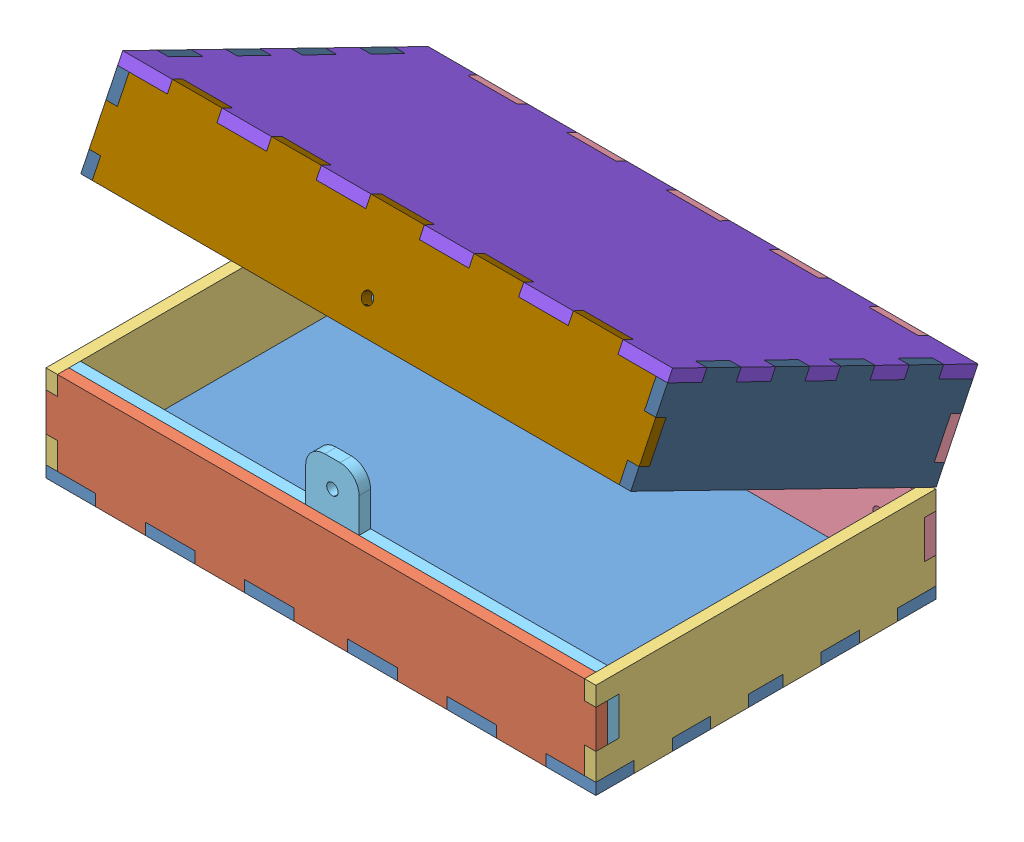
SolidWorks assembly Box_Build, configuration Default. Lengths in mm.
Overall size (144 86.89 100.06).
13 component instances, 10 part files, 34 mates.
Components (placement in the parent):
- Base_Bottom-1: Base_Bottom [Default] at (-12.3442 74.3948 151.4086) size (144 3 89)
- Base_Front-2: Base_Front [Default] at (-9.3442 77.3948 148.4086) size (144 25 3)
- Base_Side-1: Base_Side [Default] at (128.6558 77.3948 151.4086) x (0 0 -1) z (0 -1 0) size (89 3 25)
- Base_Side-2: Base_Side [Default] at (-12.3442 77.3948 151.4086) x (0 0 -1) z (0 -1 0) size (89 3 25)
- Base_Back-1: Base_Back [Default] at (-9.3442 77.3948 62.4086) size (144 25 3)
- Base_Front_Catch-1: Base_Front_Catch [Default] at (-9.3442 77.3948 145.4086) size (144 39 3)
- Hinge1-1: Hinge1 [Default] at (-5.3442 78.8948 61.4086) size (130 21.5 2)
- Hinge2-1: Hinge2 [Default] at (-5.3442 118.1948 53.3198) x (1 0 0) z (0 -0.438754 -0.898607) size (130 21.5 2)
- Base_Back-2: Base_Back [Default] at (-9.3442 120.859 55.3575) x (1 0 0) z (0 -0.438754 -0.898607) size (144 25 3)
- Lid_Top-1: Lid_Top [Default] at (-12.3442 158.5918 132.6378) x (1 0 0) z (0 0.438754 0.898607) size (144 3 89)
- Top_Front-1: Top_Front [Default] at (-9.3442 158.5918 132.6378) x (1 0 0) z (0 -0.438754 -0.898607) size (144 25 3)
- Sides-1: Sides [Default] at (128.6558 138.8225 142.2903) x (1 0 0) z (0 0.438754 0.898607) size (3 25 89)
- Sides-2: Sides [Default] at (-12.3442 138.8225 142.2903) x (1 0 0) z (0 0.438754 0.898607) size (3 25 89)
Mates (geometry in assembly coordinates):
- Coincident1: coincident aligned: plane of Base_Bottom-1 through (118.6558 77.3948 151.4086) normal (0 0 1); plane of Base_Front-2 through (-9.3442 77.3948 151.4086) normal (0 0 1)
- Coincident2: coincident aligned: plane of Base_Bottom-1 through (131.6558 77.3948 151.4086) normal (1 0 0); plane of Base_Front-2 through (131.6558 94.3948 151.4086) normal (1 0 0)
- Coincident3: coincident aligned: plane of Base_Bottom-1 through (-12.3442 74.3948 151.4086) normal (0 -1 0); plane of Base_Front-2 through (105.6558 74.3948 151.4086) normal (0 -1 0)
- Coincident5: coincident aligned: plane of Base_Front-2 through (-9.3442 77.3948 151.4086) normal (0 0 1); plane of Base_Side-1 through (131.6558 77.3948 151.4086) normal (0 0 1)
- Coincident6: coincident aligned: plane of Base_Bottom-1 through (-12.3442 74.3948 151.4086) normal (0 -1 0); plane of Base_Side-1 through (131.6558 74.3948 121.4086) normal (0 -1 0)
- Coincident7: coincident aligned: plane of Base_Front-2 through (131.6558 94.3948 151.4086) normal (1 0 0); plane of Base_Side-1 through (131.6558 77.3948 151.4086) normal (1 0 0)
- Coincident8: coincident aligned: plane of Base_Front-2 through (-9.3442 77.3948 151.4086) normal (0 0 1); plane of Base_Side-2 through (-9.3442 77.3948 151.4086) normal (0 0 1)
- Coincident9: coincident aligned: plane of Base_Bottom-1 through (-12.3442 77.3948 131.4086) normal (-1 0 0); plane of Base_Side-2 through (-12.3442 77.3948 151.4086) normal (-1 0 0)
- Coincident10: coincident aligned: plane of Base_Bottom-1 through (-12.3442 74.3948 151.4086) normal (0 -1 0); plane of Base_Side-2 through (-9.3442 74.3948 141.4086) normal (0 -1 0)
- Coincident11: coincident aligned: plane of Base_Side-1 through (131.6558 77.3948 62.4086) normal (0 0 -1); plane of Base_Back-1 through (-9.3442 77.3948 62.4086) normal (0 0 -1)
- Coincident12: coincident aligned: plane of Base_Side-1 through (131.6558 77.3948 151.4086) normal (1 0 0); plane of Base_Back-1 through (131.6558 94.3948 65.4086) normal (1 0 0)
- Coincident13: coincident aligned: plane of Base_Bottom-1 through (-12.3442 74.3948 151.4086) normal (0 -1 0); plane of Base_Back-1 through (79.6558 74.3948 65.4086) normal (0 -1 0)
- Coincident14: coincident anti-aligned: plane of Base_Front-2 through (-9.3442 77.3948 148.4086) normal (0 0 -1); plane of Base_Front_Catch-1 through (57.6558 108.3948 148.4086) normal (0 0 1)
- Coincident15: coincident aligned: plane of Base_Bottom-1 through (-12.3442 74.3948 151.4086) normal (0 -1 0); plane of Base_Front_Catch-1 through (79.6558 74.3948 148.4086) normal (0 -1 0)
- Coincident16: coincident aligned: plane of Base_Side-2 through (-12.3442 77.3948 151.4086) normal (-1 0 0); plane of Base_Front_Catch-1 through (-12.3442 94.3948 148.4086) normal (-1 0 0)
- Coincident24: coincident anti-aligned: plane of Base_Back-1 through (-9.3442 77.3948 62.4086) normal (0 0 -1); plane of Hinge1-1 through (-5.3442 78.8948 62.4086) normal (0 0 1)
- Concentric4: concentric aligned: circle of Base_Back-1; circle of Hinge1-1
- Parallel3: parallel aligned: line of Base_Back-1 through (79.6558 74.3948 62.4086) axis (1 0 0); line of Hinge1-1 through (-5.3442 78.8948 61.4086) axis (1 0 0)
- Hinge1: hinge = 0.454211 rad aligned: cylinder of Hinge2-1 through (98.6558 99.3907 61.5402) axis (-1 0 0) radius 1; cylinder of Hinge1-1 through (72.6558 99.3907 61.5402) axis (-1 0 0) radius 1; plane of Hinge2-1 through (124.6558 117.7561 52.4212) normal (1 0 0); plane of Hinge1-1 through (124.6558 78.8948 62.4086) normal (1 0 0); plane of Hinge2-1 through (-5.3442 117.7561 52.4212) normal (0 -0.438754 -0.898607); plane of Hinge1-1 through (-5.3442 78.8948 61.4086) normal (0 0 -1)
- Coincident31: coincident anti-aligned: plane of Hinge2-1 through (-5.3442 118.1948 53.3198) normal (0 0.438754 0.898607); plane of Base_Back-2 through (-9.3442 119.5428 52.6617) normal (0 -0.438754 -0.898607)
- Concentric6: concentric aligned: circle of Hinge2-1; circle of Base_Back-2
- Parallel5: parallel aligned: line of Hinge2-1 through (-5.3442 117.7561 52.4212) axis (1 0 0); line of Base_Back-2 through (26.6558 122.2386 51.3454) axis (1 0 0)
- Coincident34: coincident aligned: plane of Base_Back-2 through (131.6558 104.2664 60.1205) normal (1 0 0); plane of Lid_Top-1 through (131.6558 135.4012 78.3037) normal (1 0 0)
- Coincident35: coincident aligned: plane of Base_Back-2 through (105.6558 122.2386 51.3454) normal (0 0.898607 -0.438754); plane of Lid_Top-1 through (-12.3442 161.2877 131.3215) normal (0 0.898607 -0.438754)
- Coincident36: coincident aligned: plane of Base_Back-2 through (-9.3442 119.5428 52.6617) normal (0 -0.438754 -0.898607); plane of Lid_Top-1 through (92.6558 122.2386 51.3454) normal (0 -0.438754 -0.898607)
- Coincident37: coincident aligned: plane of Lid_Top-1 through (-12.3442 161.2877 131.3215) normal (0 0.898607 -0.438754); plane of Top_Front-1 through (105.6558 159.9714 128.6257) normal (0 0.898607 -0.438754)
- Coincident38: coincident aligned: plane of Lid_Top-1 through (131.6558 161.2877 131.3215) normal (1 0 0); plane of Top_Front-1 through (131.6558 141.9992 137.4007) normal (1 0 0)
- Coincident39: coincident aligned: plane of Lid_Top-1 through (39.6558 161.2877 131.3215) normal (0 0.438754 0.898607); plane of Top_Front-1 through (-9.3442 158.5918 132.6378) normal (0 0.438754 0.898607)
- Coincident40: coincident aligned: plane of Lid_Top-1 through (131.6558 152.5126 113.3493) normal (1 0 0); plane of Sides-1 through (131.6558 138.8225 142.2903) normal (1 0 0)
- Coincident41: coincident aligned: plane of Top_Front-1 through (-9.3442 137.5062 139.5945) normal (0 -0.898607 0.438754); plane of Sides-1 through (131.6558 138.8225 142.2903) normal (0 -0.898607 0.438754)
- Coincident42: coincident aligned: plane of Top_Front-1 through (-9.3442 158.5918 132.6378) normal (0 0.438754 0.898607); plane of Sides-1 through (131.6558 152.3016 135.709) normal (0 0.438754 0.898607)
- Coincident43: coincident anti-aligned: plane of Lid_Top-1 through (-9.3442 143.7375 95.3772) normal (-1 0 0); plane of Sides-2 through (-9.3442 138.8225 142.2903) normal (1 0 0)
- Coincident44: coincident aligned: plane of Lid_Top-1 through (-12.3442 161.2877 131.3215) normal (0 0.898607 -0.438754); plane of Sides-2 through (-9.3442 139.7887 87.2897) normal (0 0.898607 -0.438754)
- Coincident45: coincident aligned: plane of Top_Front-1 through (-9.3442 158.5918 132.6378) normal (0 0.438754 0.898607); plane of Sides-2 through (-9.3442 138.8225 142.2903) normal (0 0.438754 0.898607)
